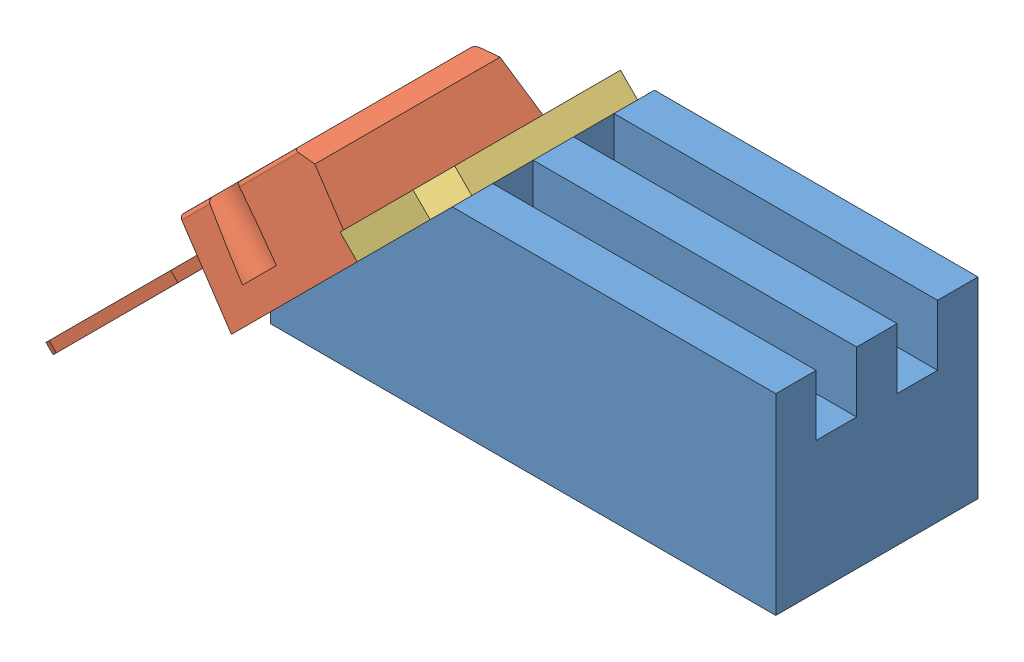
SolidWorks assembly TIP120-Heatsink, configuration Default. Lengths in mm.
Overall size (39.56 23.55 10.2).
4 component instances, 3 part files, 2 mates.
Components (placement in the parent):
- TIP120Heatsink-1: TIP120Heatsink [Default] at origin size (25 9.5 10)
- TO 220_BTA16.STEP-1: TO 220_BTA16.STEP [Default] at (0.5111 16.6931 -21.968) x (0 0 1) z (-0.707107 0.707107 0) size (10.2 28.8 4.5)
  - User Library-TO-220-4_Case TO-220___ _________.STEP-1: User Library-TO-220-4_Case TO-220___ _________.STEP [Default] at (16.7891 -23.3398 2.25) size (10.2 22.2 4.5)
  - User Library-TO-220-4_Rad Case TO-220___ _________.STEP-1: User Library-TO-220-4_Rad Case TO-220___ _________.STEP [Default] at (21.8891 -20.7398 -2.25) size (10.2 12.8 1.2)
Mates (geometry in assembly coordinates):
- Coincident1: coincident anti-aligned: plane of TIP120Heatsink-1 through (-3.5 9.5 0) normal (-0.707107 0.707107 0); plane of TO 220_BTA16.STEP-1/User Library-TO-220-4_Rad Case TO-220___ _________.STEP-1 through (-12.5632 0.4368 -0.079) normal (0.707107 -0.707107 0)
- Parallel3: parallel aligned: plane of TIP120Heatsink-1 through (-12.5 9.5 5) normal (0 0 1); plane of TO 220_BTA16.STEP-1/User Library-TO-220-4_Rad Case TO-220___ _________.STEP-1 through (-9.0276 5.6694 5.021) normal (0 0 1)
